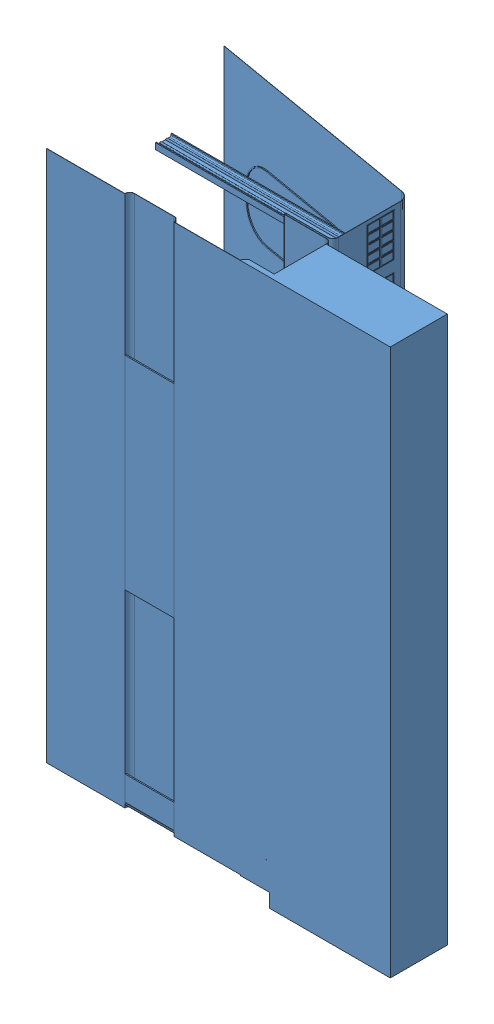
SolidWorks assembly Assem1, configuration Default. Lengths in mm.
Overall size (16149.62 22600.22 7709.85).
2 component instances, 2 part files, 0 mates.
Components (placement in the parent):
- SideWalls2-1: SideWalls2 [Default] at (1957.2926 -10700.3817 -1176.9895) size (14229.65 22600.22 7709.85)
- Uf_Abandoned_FILET-1: Uf_Abandoned_FILET [Default] at (-7707 -6124.1551 423.5905) x (-0.061049 -0.998135 0) z (0.069626 -0.004259 -0.997564) size (4640 4500 2408.97)
